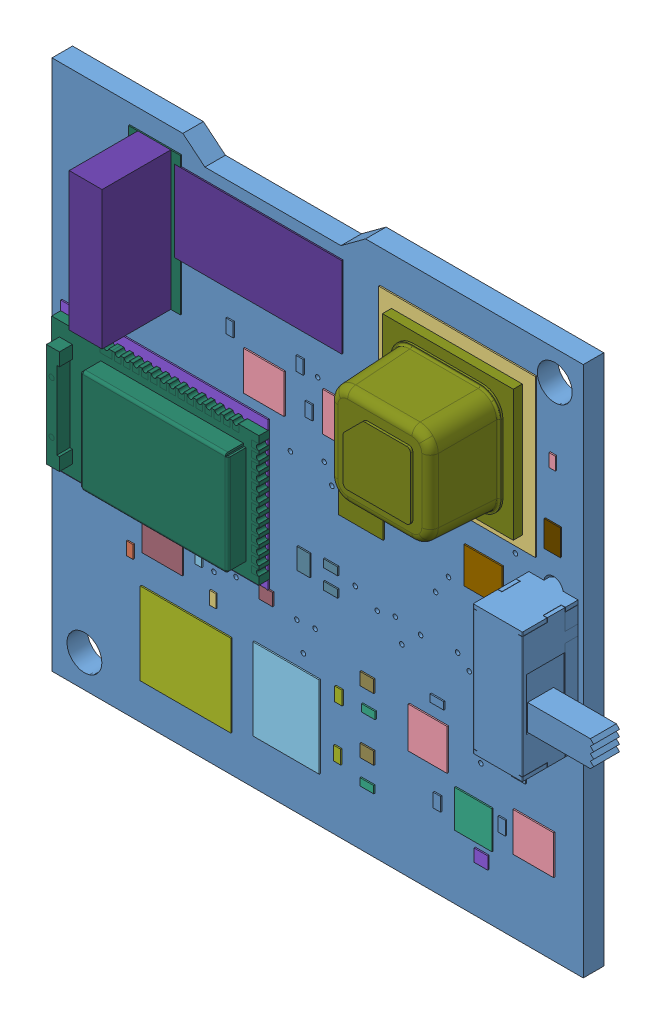
SolidWorks assembly PCB_nobatteryholder, configuration Default. Lengths in mm.
Overall size (45.6 41 9.88).
67 component instances, 38 part files, 5 mates.
Components (placement in the parent):
- PCB(2).step-1: PCB(2).step [Default] at (-23.3102 -47.5911 44.908) size (45.7 41 1.78)
  - PCB Component.step-1: PCB Component.step [Default] at origin size (45.7 41 1.78)
    - Board.step-1: Board.step [Default] at origin size (41 41 1.58)
    - 2996TR.step-1: 2996TR.step [Default] at (40.14 34.65 0) x (1 0 0) z (0 0 -1) size (13.21 12.07 0.1)
    - 2996TR.step-2: 2996TR.step [Default] at (21.69 34.65 0) x (1 0 0) z (0 0 -1) size (13.21 12.07 0.1)
    - 2996TR.step-3: 2996TR.step [Default] at (20.86 59.95 0) x (-1 0 0) z (0 0 -1) size (13.21 12.07 0.1)
    - 2996TR.step-4: 2996TR.step [Default] at (39.96 59.63 0) x (-1 0 0) z (0 0 -1) size (13.21 12.07 0.1)
    - SCD41-D-R2.step-1: SCD41-D-R2.step [Default] at (41.35 59.4 1.584) size (12.1 12.1 0.1)
    - BSS138.step-1: BSS138.step [Default] at (39.94 37.09 1.584) size (3 3.14 0.1)
    - BSS138.step-2: BSS138.step [Default] at (47.24 35.01 1.584) x (0 1 0) z (0 0 1) size (3 3.14 0.1)
    - BSS138.step-3: BSS138.step [Default] at (26.44 55.43 1.584) x (0 1 0) z (0 0 1) size (3 3.14 0.1)
    - BSS138.step-4: BSS138.step [Default] at (32.54 55.75 1.584) x (0 1 0) z (0 0 1) size (3 3.14 0.1)
    - TSV912IDT.step-1: TSV912IDT.step [Default] at (28.16 33.68 1.584) x (0 -1 0) z (0 0 1) size (6.3 5.13 0.1)
    - SGP30.step-1: SGP30.step [Default] at (42.4 33.66 1.584) x (-1 0 0) z (0 0 1) size (2.88 2.88 0.1)
    - MICS-6814.step-1: MICS-6814.step [Default] at (20.41 33.71 1.584) x (0 1 0) z (0 0 1) size (6.34 7 0.1)
    - 317030213.step-1: 317030213.step [Default] at (18.77 47.25 1.584) x (0 1 0) z (0 0 1) size (11.45 16 0.1)
    - BME280.step-1: BME280.step [Default] at (43.18 50.09 1.584) size (2.95 2.77 0.1)
    - EG1213.step-1: EG1213.step [Default] at (48.7 47.1 1.584) x (0 1 0) z (0 0 1) size (11.2 9 0.1) (hidden)
    - MC78LC50NTRGTSOT23-5_ONS.step-1: MC78LC50NTRGTSOT23-5_ONS.step [Default] at (29.4 47.4 0) x (-1 0 0) z (0 0 -1) size (2.79 3.33 0.1)
    - MIC5219-3.3YMMMSOP-8LD-PL-1_MCH.step-1: MIC5219-3.3YMMMSOP-8LD-PL-1_MCH.step [Default] at (36 47.2 0) x (-1 0 0) z (0 0 -1) size (4.9 3.53 0.1)
    - S-1318D18-M5T1U4.step-1: S-1318D18-M5T1U4.step [Default] at (43.3 46.3 0) x (1 0 0) z (0 0 -1) size (4.2 3.6 0.1)
    - MMBT3904-215.step-1: MMBT3904-215.step [Default] at (18.6 39.2 1.584) x (0 -1 0) z (0 0 1) size (3.16 3.12 0.1)
    - ECS-.327-9-16-TR.step-1: ECS-.327-9-16-TR.step [Default] at (29.5 44.1 1.584) x (0 -1 0) z (0 0 1) size (1.6 1 0.1)
    - BG306-04-A-1-0400-X-X_REVD.step-1: BG306-04-A-1-0400-X-X_REVD.step [Default] at (18 61.2 1.584) x (0 -1 0) z (0 0 1) size (10.66 4 0.1)
    - STMICROELECTRONICS_LIS3DHSTMICROELECTRONICS_LIS3DH_0_0.step-1: STMICROELECTRONICS_LIS3DHSTMICROELECTRONICS_LIS3DH_0_0.step [Default] at (33.8 50.2 1.584) x (-1 0 0) z (0 0 1) size (3.43 3.15 0.1)
    - S5B-ZR-SM4A-TF_(LF)_(SN)CONN_S5B-ZR-SM4A-TF_JST.step-1: S5B-ZR-SM4A-TF_(LF)_(SN)CONN_S5B-ZR-SM4A-TF_JST.step [Default] at (24.1 59.8 1.584) size (12.9 6.25 0.1)
    - LTST-C170KRKT.step-1: LTST-C170KRKT.step [Default] at (48.7 55.3 1.584) x (0 -1 0) z (0 0 1) size (2 1.25 0.1)
    - MCS0402MC1002FE000.step-1: MCS0402MC1002FE000.step [Default] at (39.8 33.2 1.584) x (0 -1 0) z (0 0 1) size (1.06 0.56 0.1)
    - MCS0402MC1002FE000.step-2: MCS0402MC1002FE000.step [Default] at (39.8 39.9 1.584) size (1.06 0.56 0.1)
    - MCS0402MC1002FE000.step-3: MCS0402MC1002FE000.step [Default] at (44.8 34.1 1.584) x (0 -1 0) z (0 0 1) size (1.06 0.56 0.1)
    - MCS0402MC1002FE000.step-4: MCS0402MC1002FE000.step [Default] at (46.1 38.1 1.584) x (-1 0 0) z (0 0 1) size (1.06 0.56 0.1)
    - MCS0402MC1002FE000.step-5: MCS0402MC1002FE000.step [Default] at (29.2 57.1 1.584) x (0 -1 0) z (0 0 1) size (1.06 0.56 0.1)
    - MCS0402MC1002FE000.step-6: MCS0402MC1002FE000.step [Default] at (33 53.1 1.584) size (1.06 0.56 0.1)
    - MCS0402MC1002FE000.step-7: MCS0402MC1002FE000.step [Default] at (23.8 56.9 1.584) x (0 1 0) z (0 0 1) size (1.06 0.56 0.1)
    - MCS0402MC1002FE000.step-8: MCS0402MC1002FE000.step [Default] at (29.9 54.4 1.584) x (0 1 0) z (0 0 1) size (1.06 0.56 0.1)
    - ERJPA2F1300X.step-1: ERJPA2F1300X.step [Default] at (16.1 38.2 1.584) x (0 1 0) z (0 0 1) size (1 0.5 0.1)
    - ERJPA2J821X.step-1: ERJPA2J821X.step [Default] at (22.5 38.1 1.584) x (0 1 0) z (0 0 1) size (1 0.5 0.1)
    - ERA2AEB331X.step-1: ERA2AEB331X.step [Default] at (48.7 60.4 1.584) x (0 -1 0) z (0 0 1) size (1 0.5 0.1)
    - ERJPA2F5101X.step-1: ERJPA2F5101X.step [Default] at (21.4 40.3 1.584) x (0 -1 0) z (0 0 1) size (1 0.5 0.1)
    - ERJ-2GEJ106X.step-1: ERJ-2GEJ106X.step [Default] at (34.5 36.6 1.584) size (1.06 0.56 0.1)
    - ERJ-2GEJ106X.step-2: ERJ-2GEJ106X.step [Default] at (34.4 31.6 1.584) x (-1 0 0) z (0 0 1) size (1.06 0.56 0.1)
    - ERJ-2GEJ106X.step-3: ERJ-2GEJ106X.step [Default] at (32.5 45.7 0) x (0 1 0) z (0 0 -1) size (1.06 0.56 0.1)
    - ERJ-2GEJ106X.step-4: ERJ-2GEJ106X.step [Default] at (33.4 43 0) x (0 -1 0) z (0 0 -1) size (1.06 0.56 0.1)
    - ERJ-2GEJ515X.step-1: ERJ-2GEJ515X.step [Default] at (32.2 36.5 1.584) x (0 -1 0) z (0 0 1) size (1.06 0.56 0.1)
    - ERJ-2GEJ515X.step-2: ERJ-2GEJ515X.step [Default] at (32.1 32.5 1.584) x (0 -1 0) z (0 0 1) size (1.06 0.56 0.1)
    - C0402C104K9RACAUTO.step-1: C0402C104K9RACAUTO.step [Default] at (32 47.8 0) x (0 1 0) z (0 0 -1) size (1.06 0.96 0.1)
    - C0402C104K9RACAUTO.step-2: C0402C104K9RACAUTO.step [Default] at (29.4 45.1 0) x (-1 0 0) z (0 0 -1) size (1.06 0.96 0.1)
    - C0402C104K9RACAUTO.step-3: C0402C104K9RACAUTO.step [Default] at (43.2 31.1 1.584) size (1.06 0.96 0.1)
    - CL05A225MQ5NNNC.step-1: CL05A225MQ5NNNC.step [Default] at (39.7 44.8 0) x (1 0 0) z (0 0 -1) size (1.06 0.96 0.1)
    - CL05B471KB5NNNCCAP_CL05_SAM.step-1: CL05B471KB5NNNCCAP_CL05_SAM.step [Default] at (36.1 44.8 0) x (1 0 0) z (0 0 -1) size (1 0.5 0.1)
    - JMK105BJ105KV-F.step-1: JMK105BJ105KV-F.step [Default] at (40.6 46.7 0) x (0 1 0) z (0 0 -1) size (1.06 0.56 0.1)
    - JMK105BJ105KV-F.step-2: JMK105BJ105KV-F.step [Default] at (43.6 43.7 0) x (1 0 0) z (0 0 -1) size (1.06 0.56 0.1)
    - CL05B103KO5NNNC.step-1: CL05B103KO5NNNC.step [Default] at (34.4 38.5 1.584) x (-1 0 0) z (0 0 1) size (1.06 0.96 0.1)
    - CL05B103KO5NNNC.step-2: CL05B103KO5NNNC.step [Default] at (34.4 33.7 1.584) size (1.06 0.96 0.1)
    - CL05B103KO5NNNC.step-3: CL05B103KO5NNNC.step [Default] at (32.1 43 0) x (0 -1 0) z (0 0 -1) size (1.06 0.96 0.1)
    - CL05A106MP5NUNC.step-1: CL05A106MP5NUNC.step [Default] at (26.6 40.4 1.584) x (-1 0 0) z (0 0 1) size (1.06 0.96 0.1)
    - 04025A120FAT2A.step-1: 04025A120FAT2A.step [Default] at (31.6 43.3 1.584) x (-1 0 0) z (0 0 1) size (1.1 0.6 0.1)
    - 04025A120FAT2A.step-2: 04025A120FAT2A.step [Default] at (31.6 44.8 1.584) x (-1 0 0) z (0 0 1) size (1.1 0.6 0.1)
- Micro.step-1: Micro.step [Default] at (-4.5401 -1.0595 46.492) x (0 1 0) z (1 0 0) size (10 2.2 16)
- SCD41.step-1: SCD41.step [Default] at (18.0381 11.8123 47.292) size (10.1 10.1 6.31)
- Programmatore.stp-1: Programmatore.stp [Default] at (-5.3139 13.6094 46.492) x (0 1 0) z (0 0 1) size (10.66 5 5.4)
  - Body.stp-1: Body.stp [Default] at (0 0 0.1) size (10.66 2.54 5.3)
  - Pins.stp-1: Pins.stp [Default] at origin size (8.44 5 0.1)
- EG1213--3DModel-STEP-520916.step-1: EG1213--3DModel-STEP-520916.step [Default] at (25.3922 -0.5224 47.292) x (1 0 0) z (0 -1 0) size (8.8 7.9 10)
- SGP30.step-1: SGP30.step [Default] at (19.3022 -14.1458 46.492) x (-1 0 0) z (0 1 0) size (2.88 2.88 0.1) (suppressed, hidden)
- SGP30.step-3: SGP30.step [Default] at (44.7999 -15.0699 54.1823) x (1 0 0) z (0 -1 0) size (2.88 2.88 0.1) (suppressed, hidden)
- SGP30.step-5: SGP30.step [Default] at (45.0699 -18.2823 49.3168) x (1 0 0) z (0 -1 0) size (2.88 2.88 0.1) (suppressed, hidden)
Mates (geometry in assembly coordinates):
- Coincidente8: coincident anti-aligned: plane of PCB(2).step-1/PCB Component.step-1/Board.step-1 through (7.1898 -0.0911 46.492) normal (0 0 1); plane of Micro.step-1 through (-4.5401 -1.0595 46.492) normal (0 0 -1)
- Coincidente9: coincident anti-aligned: plane of SCD41.step-1 through (12.9881 6.7623 46.492) normal (0 0 -1); plane of PCB(2).step-1/PCB Component.step-1/Board.step-1 through (7.1898 -0.0911 46.492) normal (0 0 1)
- Parallelo4: parallel aligned: plane of PCB(2).step-1/PCB Component.step-1/SCD41-D-R2.step-1 through (18.0398 11.8089 46.592) normal (0 0 1); plane of SCD41.step-1 through (20.338 9.2124 52.772) normal (0 0 1)
- Coincidente11: coincident anti-aligned: plane of PCB(2).step-1/PCB Component.step-1/Board.step-1 through (7.1898 -0.0911 46.492) normal (0 0 1); plane of Programmatore.stp-1/Pins.stp-1 through (-2.8159 17.0114 46.492) normal (0 0 -1)
- Coincidente25: coincident anti-aligned: plane of PCB(2).step-1/PCB Component.step-1/Board.step-1 through (7.1898 -0.0911 46.492) normal (0 0 1); plane of EG1213--3DModel-STEP-520916.step-1 through (25.3922 -0.5224 46.492) normal (0 0 -1)
